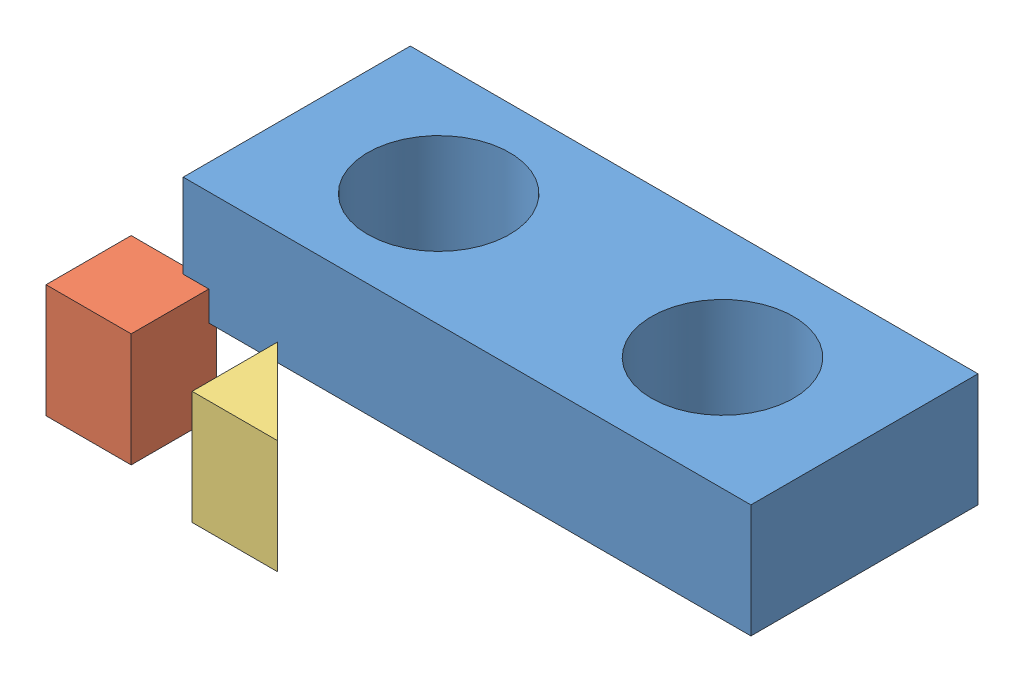
SolidWorks assembly Assembly 56, configuration Default. Lengths in mm.
Overall size (140.31 44.21 74.95).
3 component instances, 3 part files, 0 mates.
Components (placement in the parent):
- Block_circles_2013-1: Block_circles_2013 [Default] at (-9.2805 46.7881 123.8991) size (127 25.4 50.8)
- Square_2013-1: Square_2013 [Default] at (-22.5954 27.9785 141.2747) size (19.05 25.4 19.05)
- Traingle_2013-1: Traingle_2013 [Default] at (16.8691 30.4369 148.0509) size (19.05 25.4 19.05)
